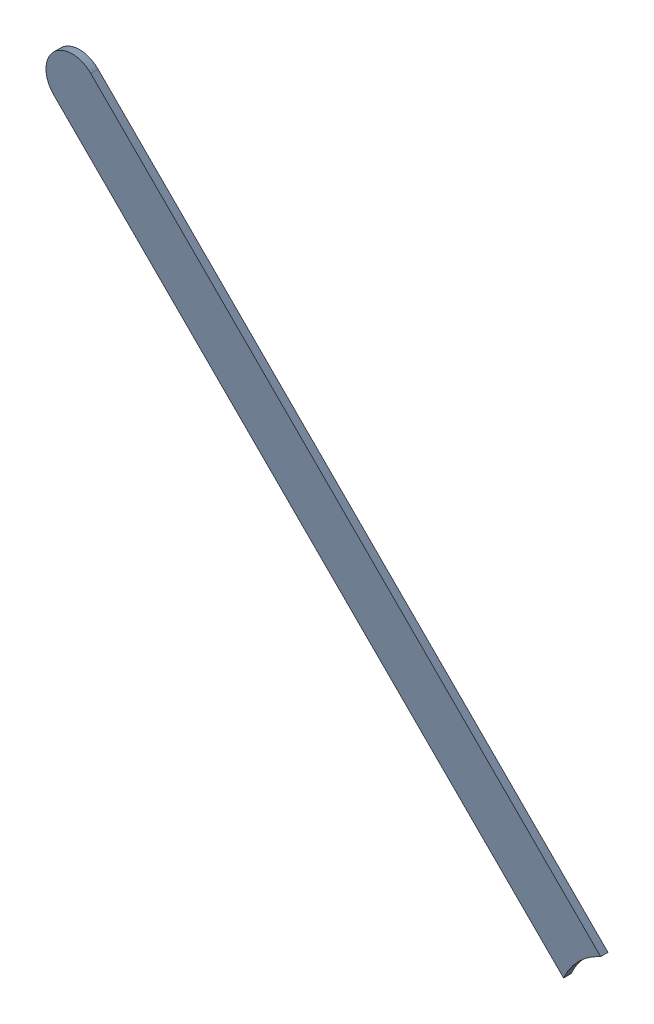
SolidWorks assembly Track (8.493mm,33.107mm)(11.2mm,30.4mm) on Bottom Layer, configuration Predeterminado. Lengths in mm.
Overall size (2.69 2.69 0.04).
2 component instances, 1 part files, 0 mates.
Components (placement in the parent):
- Track (8.493mm,33.107mm)(11.2mm,30.4mm) on Bottom Layer-1-1: Track (8.493mm,33.107mm)(11.2mm,30.4mm) on Bottom Layer-1 [Predeterminado] at (-68.317 -44.187 -0.4013) size (2.69 2.69 0.04)
  - Track (8.493mm,33.107mm)(11.2mm,30.4mm) on Bottom Layer-Part-1-1: Track (8.493mm,33.107mm)(11.2mm,30.4mm) on Bottom Layer-Part-1 [Predeterminado] at origin size (2.69 2.69 0.04)
